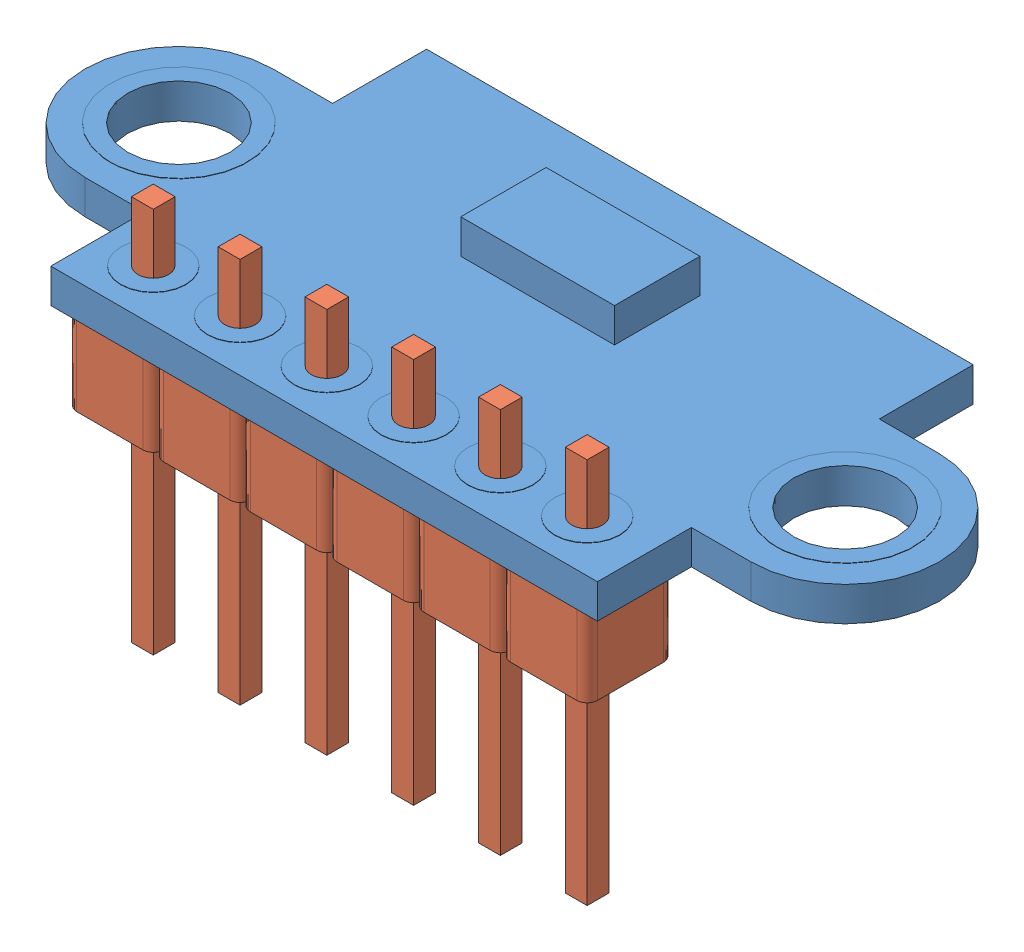
SolidWorks assembly vl53l0x, configuration Default. Lengths in mm.
Overall size (25 11.3 11).
7 component instances, 2 part files, 4 mates.
Components (placement in the parent):
- vl53l0x_PCB-1: vl53l0x_PCB [Default] at origin size (25 3 11)
- pin_header-1: pin_header [Default] at (-6.5 -2.54 4) size (2.54 11.3 2.54)
- pin_header-2: pin_header [Default] at (-3.96 -2.54 4) size (2.54 11.3 2.54)
- pin_header-3: pin_header [Default] at (-1.42 -2.54 4) size (2.54 11.3 2.54)
- pin_header-4: pin_header [Default] at (1.12 -2.54 4) size (2.54 11.3 2.54)
- pin_header-5: pin_header [Default] at (3.66 -2.54 4) size (2.54 11.3 2.54)
- pin_header-6: pin_header [Default] at (6.2 -2.54 4) size (2.54 11.3 2.54)
Mates (geometry in assembly coordinates):
- Совпадение1: coincident anti-aligned: plane of vl53l0x_PCB-1 through (-9.75 0 0) normal (0 -1 0); plane of pin_header-1 through (-7.47 0 4.97) normal (0 1 0)
- Расстояние1: distance = 0.23 mm aligned: plane of pin_header-1 through (-7.77 0 4.97) normal (-1 0 0); plane of vl53l0x_PCB-1 through (-8 1 5.5) normal (-1 0 0)
- Расстояние2: distance = 0.23 mm aligned: plane of pin_header-1 through (-5.53 0 5.27) normal (0 0 1); plane of vl53l0x_PCB-1 through (8 1 5.5) normal (0 0 1)
- Совпадение6: coordinate: point of vl53l0x_PCB-1
